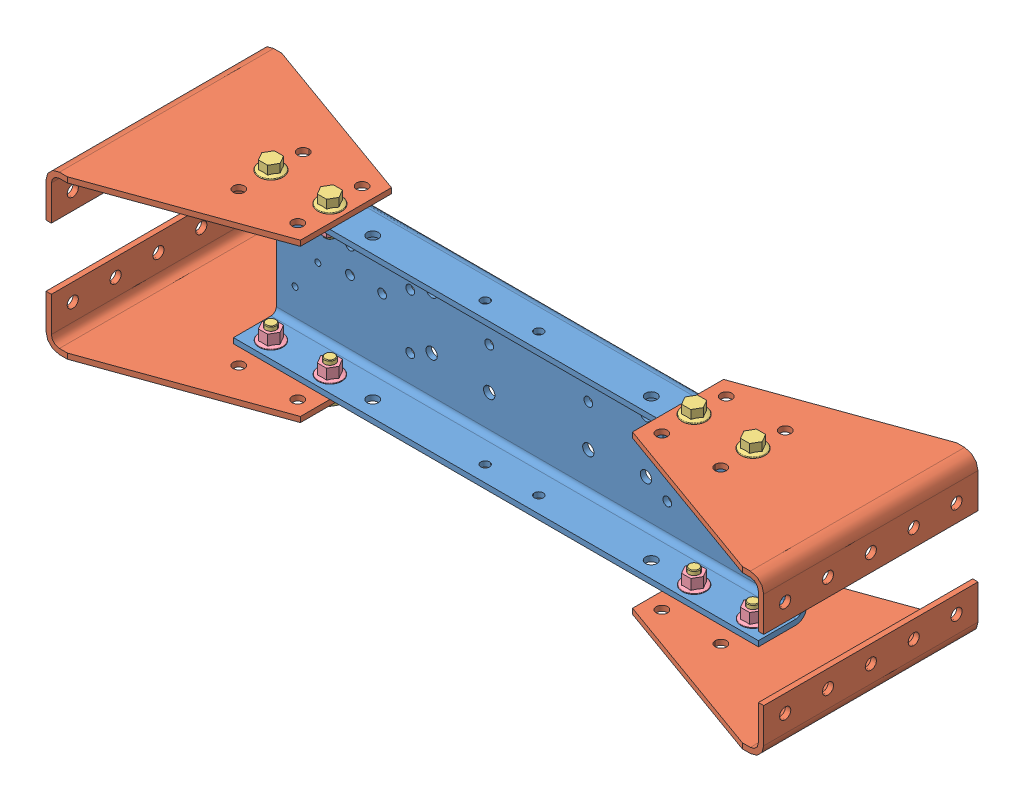
SolidWorks assembly SUB-1700-067, configuration Exploded. Lengths in mm.
Overall size (850.9 213.23 254).
45 component instances, 4 part files, 111 mates.
Components (placement in the parent):
- 2504-CC2-1: 2504-CC2 [Default] at (0 0 -38.1) x (-1 0 0) z (0 0 -1) size (622.3 174.62 57.15)
- 2518-CC2-1: 2518-CC2 [2518-CC2-001] at (-425.45 93.6625 0) size (228.6 57.15 254)
- 2518-CC2-2: 2518-CC2 [2518-CC2-001] at (-425.45 -93.6625 0) x (1 0 0) z (0 0 -1) size (228.6 57.15 254)
- 2518-CC2-3: 2518-CC2 [2518-CC2-001] at (425.45 93.6625 0) x (-1 0 0) z (0 0 -1) size (228.6 57.15 254)
- 2518-CC2-4: 2518-CC2 [2518-CC2-001] at (425.45 -93.6625 0) x (-1 0 0) z (0 0 1) size (228.6 57.15 254)
- 08130XXXFH8Y-1: 08130XXXFH8Y [08130125FH8Y] at (-215.9 -93.6625 0) x (0.866025 0 0.5) z (0 -1 0) size (28.77 28.77 44.7)
- 08130XXXFH8Y-5: 08130XXXFH8Y [08130125FH8Y] at (215.9 93.6625 0) x (0.866025 0 -0.5) z (0 1 0) size (28.77 28.77 44.7)
- 08130XXXFH8Y-4: 08130XXXFH8Y [08130125FH8Y] at (215.9 -93.6625 0) x (0.866025 0 0.5) z (0 -1 0) size (28.77 28.77 44.7)
- 08130XXXFH8Y-8: 08130XXXFH8Y [08130125FH8Y] at (-215.9 93.6625 0) x (0 0 -1) z (0 1 0) size (28.77 28.77 44.7)
- 08130XXXFH8Y-2: 08130XXXFH8Y [08130125FH8Y] at (-285.75 -93.6625 0) x (0.866025 0 0.5) z (0 -1 0) size (28.77 28.77 44.7)
- 08130XXXFH8Y-7: 08130XXXFH8Y [08130125FH8Y] at (-285.75 93.6625 0) x (0 0 -1) z (0 1 0) size (28.77 28.77 44.7)
- 08130XXXFH8Y-6: 08130XXXFH8Y [08130125FH8Y] at (285.75 93.6625 0) x (0.866025 0 -0.5) z (0 1 0) size (28.77 28.77 44.7)
- 08130XXXFH8Y-3: 08130XXXFH8Y [08130125FH8Y] at (285.75 -93.6625 0) x (0.866025 0 0.5) z (0 -1 0) size (28.77 28.77 44.7)
- XXXXFLN8Y-1: XXXXFLN8Y [0813FLN8Y] at (-285.75 -80.9625 0) x (0 0 1) z (0 1 0) size (28.18 28.18 14.1)
- XXXXFLN8Y-4: XXXXFLN8Y [0813FLN8Y] at (-215.9 80.9625 0) x (0 0 -1) z (0 -1 0) size (28.18 28.18 14.1)
- XXXXFLN8Y-3: XXXXFLN8Y [0813FLN8Y] at (-285.75 80.9625 0) x (0.866025 0 0.5) z (0 -1 0) size (28.18 28.18 14.1)
- XXXXFLN8Y-2: XXXXFLN8Y [0813FLN8Y] at (-215.9 -80.9625 0) x (0 0 1) z (0 1 0) size (28.18 28.18 14.1)
- XXXXFLN8Y-6: XXXXFLN8Y [0813FLN8Y] at (215.9 80.9625 0) x (0.866025 0 0.5) z (0 -1 0) size (28.18 28.18 14.1)
- XXXXFLN8Y-8: XXXXFLN8Y [0813FLN8Y] at (215.9 -80.9625 0) x (0.866025 0 0.5) z (0 1 0) size (28.18 28.18 14.1)
- XXXXFLN8Y-5: XXXXFLN8Y [0813FLN8Y] at (285.75 80.9625 0) x (0.866025 0 0.5) z (0 -1 0) size (28.18 28.18 14.1)
- XXXXFLN8Y-7: XXXXFLN8Y [0813FLN8Y] at (285.75 -80.9625 0) x (0.866025 0 0.5) z (0 1 0) size (28.18 28.18 14.1)
- 08130XXXFH8Y-19: 08130XXXFH8Y [08130125FH8Y] at (-431.8 57.15 101.6) x (0 0.357656 -0.933853) z (-1 0 0) size (28.77 28.77 44.7) (suppressed, hidden)
- XXXXFLN8Y-18: XXXXFLN8Y [0813FLN8Y] at (-419.1 57.15 -101.6) x (0 -0.924225 -0.381849) z (1 0 0) size (28.18 28.18 14.1) (suppressed, hidden)
- 08130XXXFH8Y-20: 08130XXXFH8Y [08130125FH8Y] at (-431.8 57.15 -101.6) x (0 0.357656 -0.933853) z (-1 0 0) size (28.77 28.77 44.7) (suppressed, hidden)
- XXXXFLN8Y-19: XXXXFLN8Y [0813FLN8Y] at (-419.1 57.15 0) x (0 -0.924225 -0.381849) z (1 0 0) size (28.18 28.18 14.1) (suppressed, hidden)
- 08130XXXFH8Y-21: 08130XXXFH8Y [08130125FH8Y] at (-431.8 57.15 0) x (0 0.357656 -0.933853) z (-1 0 0) size (28.77 28.77 44.7) (suppressed, hidden)
- XXXXFLN8Y-20: XXXXFLN8Y [0813FLN8Y] at (-419.1 57.15 101.6) x (0 -0.924225 -0.381849) z (1 0 0) size (28.18 28.18 14.1) (suppressed, hidden)
- 08130XXXFH8Y-15: 08130XXXFH8Y [08130125FH8Y] at (-431.8 -57.15 101.6) x (0 0.357656 -0.933853) z (-1 0 0) size (28.77 28.77 44.7) (suppressed, hidden)
- XXXXFLN8Y-15: XXXXFLN8Y [0813FLN8Y] at (-419.1 -57.15 101.6) x (0 -0.924225 -0.381849) z (1 0 0) size (28.18 28.18 14.1) (suppressed, hidden)
- 08130XXXFH8Y-16: 08130XXXFH8Y [08130125FH8Y] at (-431.8 -57.15 -101.6) x (0 0.357656 -0.933853) z (-1 0 0) size (28.77 28.77 44.7) (suppressed, hidden)
- XXXXFLN8Y-16: XXXXFLN8Y [0813FLN8Y] at (-419.1 -57.15 0) x (0 -0.924225 -0.381849) z (1 0 0) size (28.18 28.18 14.1) (suppressed, hidden)
- 08130XXXFH8Y-17: 08130XXXFH8Y [08130125FH8Y] at (-431.8 -57.15 0) x (0 0.357656 -0.933853) z (-1 0 0) size (28.77 28.77 44.7) (suppressed, hidden)
- XXXXFLN8Y-17: XXXXFLN8Y [0813FLN8Y] at (-419.1 -57.15 -101.6) x (0 -0.924225 -0.381849) z (1 0 0) size (28.18 28.18 14.1) (suppressed, hidden)
- 08130XXXFH8Y-12: 08130XXXFH8Y [08130125FH8Y] at (431.8 -57.15 -101.6) x (0 0.999661 0.026036) z (1 0 0) size (28.77 28.77 44.7) (suppressed, hidden)
- XXXXFLN8Y-12: XXXXFLN8Y [0813FLN8Y] at (419.1 -57.15 -101.6) x (0 0 1) z (-1 0 0) size (28.18 28.18 14.1) (suppressed, hidden)
- 08130XXXFH8Y-13: 08130XXXFH8Y [08130125FH8Y] at (431.8 -57.15 0) x (0 0.999661 0.026036) z (1 0 0) size (28.77 28.77 44.7) (suppressed, hidden)
- XXXXFLN8Y-13: XXXXFLN8Y [0813FLN8Y] at (419.1 -57.15 0) x (0 0 1) z (-1 0 0) size (28.18 28.18 14.1) (suppressed, hidden)
- 08130XXXFH8Y-14: 08130XXXFH8Y [08130125FH8Y] at (431.8 -57.15 101.6) x (0 0.999661 0.026036) z (1 0 0) size (28.77 28.77 44.7) (suppressed, hidden)
- XXXXFLN8Y-14: XXXXFLN8Y [0813FLN8Y] at (419.1 -57.15 101.6) x (0 0 1) z (-1 0 0) size (28.18 28.18 14.1) (suppressed, hidden)
- 08130XXXFH8Y-9: 08130XXXFH8Y [08130125FH8Y] at (431.8 57.15 101.6) x (0 0.999661 0.026036) z (1 0 0) size (28.77 28.77 44.7) (suppressed, hidden)
- XXXXFLN8Y-9: XXXXFLN8Y [0813FLN8Y] at (419.1 57.15 101.6) x (0 0 1) z (-1 0 0) size (28.18 28.18 14.1) (suppressed, hidden)
- 08130XXXFH8Y-10: 08130XXXFH8Y [08130125FH8Y] at (431.8 57.15 -101.6) x (0 0.999661 0.026036) z (1 0 0) size (28.77 28.77 44.7) (suppressed, hidden)
- XXXXFLN8Y-10: XXXXFLN8Y [0813FLN8Y] at (419.1 57.15 -101.6) x (0 0 1) z (-1 0 0) size (28.18 28.18 14.1) (suppressed, hidden)
- 08130XXXFH8Y-11: 08130XXXFH8Y [08130125FH8Y] at (431.8 57.15 0) x (0 0.248909 -0.968527) z (1 0 0) size (28.77 28.77 44.7) (suppressed, hidden)
- XXXXFLN8Y-11: XXXXFLN8Y [0813FLN8Y] at (419.1 57.15 0) x (0 0 1) z (-1 0 0) size (28.18 28.18 14.1) (suppressed, hidden)
Mates (geometry in assembly coordinates):
- Distance1: distance = 38.1 mm anti-aligned: plane of 2504-CC2-1 through (0 0 -38.1) normal (0 0 -1)
- Coincident53: coincident anti-aligned: unknown of 2504-CC2-1
- Coincident78: coincident aligned: unknown of 2504-CC2-1
- Coincident96: coincident aligned: plane of ?; plane of assembly
- Distance2: distance = 93.6625 mm aligned: plane of ?; plane of assembly
- Distance3: distance = 425.45 mm aligned: plane of ?; plane of assembly
- Coincident97: coincident anti-aligned: plane of ?; plane of assembly
- Distance4: distance = 425.45 mm aligned: plane of ?; plane of assembly
- Distance5: distance = 93.6625 mm anti-aligned: plane of ?; plane of assembly
- Coincident98: coincident anti-aligned: plane of ?; plane of assembly
- Distance6: distance = 425.45 mm anti-aligned: plane of ?; plane of assembly
- Distance7: distance = 93.6625 mm aligned: plane of ?; plane of assembly
- Coincident99: coincident aligned: plane of ?; plane of assembly
- Distance8: distance = 425.45 mm anti-aligned: plane of ?; plane of assembly
- Distance9: distance = 93.6625 mm anti-aligned: plane of ?; plane of assembly
- Concentric1: concentric anti-aligned: cylinder of ?; cylinder of ?
- Coincident100: coincident anti-aligned: plane of ?; plane of ?
- Concentric2: concentric anti-aligned: cylinder of ?; cylinder of ?
- Coincident101: coincident anti-aligned: plane of ?; plane of ?
- Concentric3: concentric anti-aligned: cylinder of ?; cylinder of ?
- Concentric4: concentric anti-aligned: cylinder of ?; cylinder of ?
- Coincident102: coincident anti-aligned: plane of ?; plane of ?
- Coincident103: coincident anti-aligned: plane of ?; plane of ?
- Concentric5: concentric anti-aligned: cylinder of ?; cylinder of ?
- Concentric6: concentric anti-aligned: cylinder of ?; cylinder of ?
- Coincident104: coincident anti-aligned: plane of ?; plane of ?
- Coincident105: coincident anti-aligned: plane of ?; plane of ?
- Coincident106: coincident anti-aligned: plane of ?; plane of ?
- Concentric7: concentric anti-aligned: cylinder of ?; cylinder of ?
- Coincident107: coincident anti-aligned: plane of ?; plane of ?
- Concentric8: concentric anti-aligned: cylinder of ?; cylinder of ?
- Concentric9: concentric anti-aligned: cylinder of ?; cylinder of ?
- Concentric10: concentric anti-aligned: cylinder of ?; cylinder of ?
- Coincident108: coincident anti-aligned: unknown of 2504-CC2-1
- Coincident109: coincident anti-aligned: unknown of 2504-CC2-1
- Concentric11: concentric anti-aligned: cylinder of ?; cylinder of ?
- Concentric12: concentric anti-aligned: cylinder of ?; cylinder of ?
- Coincident110: coincident anti-aligned: unknown of 2504-CC2-1
- Coincident111: coincident anti-aligned: unknown of 2504-CC2-1
- Concentric13: concentric anti-aligned: cylinder of ?; cylinder of ?
- Concentric14: concentric anti-aligned: cylinder of ?; cylinder of ?
- Coincident112: coincident anti-aligned: unknown of 2504-CC2-1
- Coincident113: coincident anti-aligned: unknown of 2504-CC2-1
- Concentric15: concentric anti-aligned: cylinder of ?; cylinder of ?
- Coincident114: coincident anti-aligned: unknown of 2504-CC2-1
- Concentric16: concentric anti-aligned: cylinder of ?; cylinder of ?
- Coincident115: coincident anti-aligned: unknown of 2504-CC2-1
- Parallel1: parallel: line of ?; plane of assembly
- Parallel2: parallel: line of ?; plane of assembly
- Parallel3: parallel: line of ?; plane of assembly
- Parallel4: parallel: line of ?; plane of assembly
- Parallel5: parallel: line of ?; plane of assembly
- Parallel6: parallel: line of ?; plane of assembly
- Parallel7: parallel: line of ?; plane of assembly
- Parallel8: parallel: line of ?; plane of assembly
- Parallel9: parallel: line of ?; plane of assembly
- Parallel10: parallel: line of ?; plane of assembly
- Parallel11: parallel: line of ?; plane of assembly
- Parallel12: parallel: line of ?; plane of assembly
- Parallel13: parallel: line of ?; plane of assembly
- Parallel14: parallel: line of ?; plane of assembly
- Parallel15: parallel: line of ?; plane of assembly
- Parallel16: parallel: line of ?; plane of assembly
- Concentric17: concentric aligned: cylinder of ?; cylinder of ?
- Distance10: distance = 6.35 mm anti-aligned: plane of ?; plane of ?
- Concentric18: concentric anti-aligned: cylinder of ?; cylinder of ?
- Coincident117: coincident anti-aligned: plane of ?; plane of ?
- Concentric19: concentric aligned: cylinder of ?; cylinder of ?
- Distance11: distance = 6.35 mm anti-aligned: plane of ?; plane of ?
- Concentric20: concentric anti-aligned: cylinder of ?; cylinder of ?
- Coincident119: coincident anti-aligned: plane of ?; plane of ?
- Concentric21: concentric aligned: cylinder of ?; cylinder of ?
- Distance12: distance = 6.35 mm anti-aligned: plane of ?; plane of ?
- Coincident121: coincident anti-aligned: plane of ?; plane of ?
- Concentric22: concentric anti-aligned: cylinder of ?; cylinder of ?
- Concentric23: concentric aligned: cylinder of ?; cylinder of ?
- Distance13: distance = 6.35 mm anti-aligned: plane of ?; plane of ?
- Coincident123: coincident anti-aligned: plane of ?; plane of ?
- Concentric24: concentric anti-aligned: cylinder of ?; cylinder of ?
- Concentric25: concentric aligned: cylinder of ?; cylinder of ?
- Distance14: distance = 6.35 mm anti-aligned: plane of ?; plane of ?
- Coincident125: coincident anti-aligned: plane of ?; plane of ?
- Concentric26: concentric anti-aligned: cylinder of ?; cylinder of ?
- Concentric27: concentric aligned: cylinder of ?; cylinder of ?
- Distance15: distance = 6.35 mm anti-aligned: plane of ?; plane of ?
- Coincident127: coincident anti-aligned: plane of ?; plane of ?
- Concentric28: concentric anti-aligned: cylinder of ?; cylinder of ?
- Concentric29: concentric aligned: cylinder of ?; cylinder of ?
- Distance16: distance = 6.35 mm anti-aligned: plane of ?; plane of ?
- Coincident129: coincident anti-aligned: plane of ?; plane of ?
- Concentric30: concentric anti-aligned: cylinder of ?; cylinder of ?
- Concentric31: concentric aligned: cylinder of ?; cylinder of ?
- Distance17: distance = 6.35 mm anti-aligned: plane of ?; plane of ?
- Coincident131: coincident anti-aligned: plane of ?; plane of ?
- Concentric32: concentric anti-aligned: cylinder of ?; cylinder of ?
- Concentric33: concentric aligned: cylinder of ?; cylinder of ?
- Distance18: distance = 6.35 mm anti-aligned: plane of ?; plane of ?
- Coincident133: coincident anti-aligned: plane of ?; plane of ?
- Concentric34: concentric anti-aligned: cylinder of ?; cylinder of ?
- Concentric35: concentric aligned: cylinder of ?; cylinder of ?
- Distance19: distance = 6.35 mm anti-aligned: plane of ?; plane of ?
- Concentric36: concentric aligned: cylinder of ?; cylinder of ?
- Distance20: distance = 6.35 mm anti-aligned: plane of ?; plane of ?
- Coincident136: coincident anti-aligned: plane of ?; plane of ?
- Concentric37: concentric anti-aligned: cylinder of ?; cylinder of ?
- Coincident137: coincident anti-aligned: plane of ?; plane of ?
- Concentric38: concentric anti-aligned: cylinder of ?; cylinder of ?
- Concentric39: concentric aligned: cylinder of ?; cylinder of ?
- Distance21: distance = 6.35 mm anti-aligned: plane of ?; plane of ?
- Coincident139: coincident anti-aligned: plane of ?; plane of ?
- Concentric40: concentric anti-aligned: 
